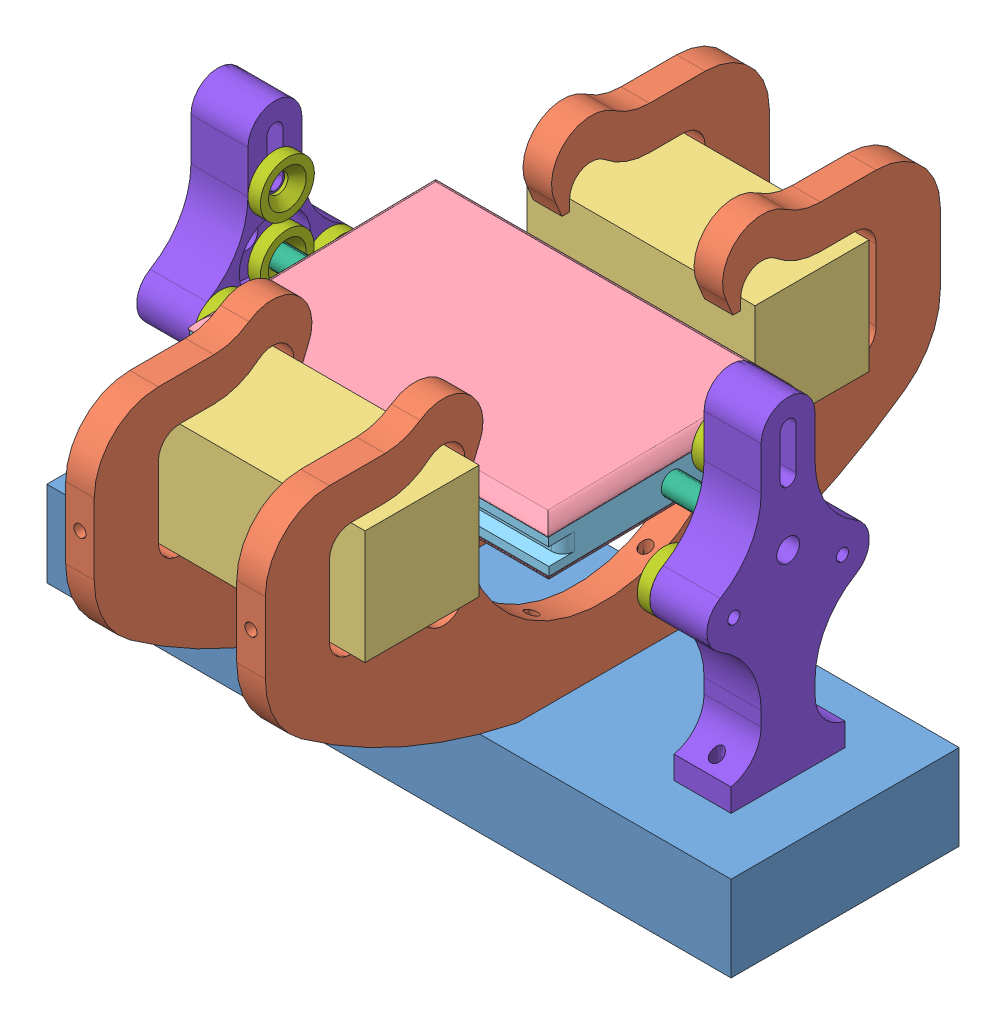
SolidWorks assembly solar motor, configuration Default. Lengths in mm.
Overall size (152.4 93 150.35).
19 component instances, 8 part files, 42 mates.
Components (placement in the parent):
- base-1: base [Default] at origin size (152.4 19.05 50.8)
- Magnet Support Arm-1: Magnet Support Arm [Default] at (53.975 63.5 25.4) x (0 0 -1) z (1 0 0) size (150.35 70.8 6.35)
- Magnet Support Arm-2: Magnet Support Arm [Default] at (92.075 63.5 25.4) x (0 0 -1) z (1 0 0) size (150.35 70.8 6.35)
- 1X1X2 c8 magnet-1: 1X1X2 c8 magnet [Default] at (101.6 50.8 -5.325) x (0 1 0) z (0 0 1) size (25.4 50.8 25.4)
- 1X1X2 c8 magnet-2: 1X1X2 c8 magnet [Default] at (50.8 50.8 81.525) x (0 0 -1) z (0 -1 0) size (25.4 50.8 25.4)
- 55X80 solar panel-1: 55X80 solar panel [Default] at (33.7861 66.8543 53.0591) x (1 0 0) z (0 0.999864 0.016493) size (80.15 55.15 2.73)
- Rotor Frame-1: Rotor Frame [Default] at (33.8861 59.237 52.8334) x (1 0 0) z (0 -0.016493 0.999864) size (80 7.62 55)
- 55X80 solar panel-2: 55X80 solar panel [Default] at (113.8861 59.2353 52.9334) x (-1 0 0) z (0 -0.999864 -0.016493) size (80.15 55.15 2.73)
- center rod-1: center rod [Default] at (26.3931 63.5 25.4) x (0 -0.960455 0.278435) z (0 0.278435 0.960455) size (4.9 99.57 4.9)
- magnet-1: magnet [Default] at (127 63.5 25.4) x (0 0.978601 0.205765) z (0 -0.205765 0.978601) size (12.01 2.78 12.01)
- magnet-2: magnet [Default] at (25.3543 63.5 25.4) x (0 -0.673541 -0.73915) z (0 -0.73915 0.673541) size (12.01 2.78 12.01)
- Rotor Suport-1: Rotor Suport [Default] at (12.7 63.5 25.4) x (0 0 -1) z (1 0 0) size (36.21 73.95 12.7)
- Rotor Suport-2: Rotor Suport [Default] at (139.7 63.5 25.4) x (0 0 1) z (-1 0 0) size (36.21 73.95 12.7)
- magnet-3: magnet [Default] at (25.4 77.47 25.4) x (0 -0.586567 -0.8099) z (0 -0.8099 0.586567) size (12.01 2.78 12.01)
- magnet-4: magnet [Default] at (25.4 56.515 37.4984) x (0 0.573393 -0.819281) z (0 -0.819281 -0.573393) size (12.01 2.78 12.01)
- magnet-5: magnet [Default] at (25.4 56.515 13.3016) x (0 0.225875 -0.974156) z (0 -0.974156 -0.225875) size (12.01 2.78 12.01)
- magnet-6: magnet [Default] at (127 77.47 25.4) x (0 0.532218 0.846608) z (0 -0.846608 0.532218) size (12.01 2.78 12.01)
- magnet-7: magnet [Default] at (127 56.515 37.4984) x (0 0.365722 0.930724) z (0 -0.930724 0.365722) size (12.01 2.78 12.01)
- magnet-8: magnet [Default] at (127 56.515 13.3016) x (0 0.869069 0.494691) z (0 -0.494691 0.869069) size (12.01 2.78 12.01)
Mates (geometry in assembly coordinates):
- Coincident1: coincident anti-aligned: plane of base-1 through (0 19.05 0) normal (0 1 0); plane of Magnet Support Arm-1 through (60.325 19.05 44.45) normal (0 -1 0)
- Coincident2: coincident anti-aligned: plane of base-1 through (0 19.05 0) normal (0 1 0); plane of Magnet Support Arm-2 through (98.425 19.05 44.45) normal (0 -1 0)
- Concentric1: concentric aligned: cylinder of base-1 through (95.25 19.05 12.7) axis (0 -1 0) radius 1.5875; cylinder of Magnet Support Arm-2 through (95.25 19.05 12.7) axis (0 -1 0) radius 1.3526
- Concentric2: concentric aligned: cylinder of base-1 through (95.25 19.05 38.1) axis (0 -1 0) radius 1.5875; cylinder of Magnet Support Arm-2 through (95.25 19.05 38.1) axis (0 -1 0) radius 1.3526
- Concentric3: concentric aligned: cylinder of base-1 through (57.15 19.05 38.1) axis (0 -1 0) radius 1.5875; cylinder of Magnet Support Arm-1 through (57.15 19.05 38.1) axis (0 -1 0) radius 1.3526
- Concentric4: concentric aligned: cylinder of base-1 through (57.15 19.05 12.7) axis (0 -1 0) radius 1.5875; cylinder of Magnet Support Arm-1 through (57.15 19.05 12.7) axis (0 -1 0) radius 1.3526
- Coincident3: coincident anti-aligned: plane of Magnet Support Arm-2 through (98.425 50.8 -30.725) normal (0 1 0); plane of 1X1X2 c8 magnet-1 through (50.8 50.8 -5.325) normal (0 -1 0)
- Coincident4: coincident anti-aligned: plane of Magnet Support Arm-2 through (98.425 50.8 -5.325) normal (0 0 -1); plane of 1X1X2 c8 magnet-1 through (50.8 50.8 -5.325) normal (0 0 1)
- Coincident5: coincident anti-aligned: plane of Magnet Support Arm-2 through (98.425 50.8 81.525) normal (0 1 0); plane of 1X1X2 c8 magnet-2 through (101.6 50.8 81.525) normal (0 -1 0)
- Coincident6: coincident anti-aligned: plane of Magnet Support Arm-1 through (60.325 50.8 56.125) normal (0 0 1); plane of 1X1X2 c8 magnet-2 through (101.6 50.8 56.125) normal (0 0 -1)
- Coincident7: coincident aligned: plane of 1X1X2 c8 magnet-1 through (101.6 50.8 -5.325) normal (1 0 0); plane of 1X1X2 c8 magnet-2 through (101.6 50.8 81.525) normal (1 0 0)
- Distance1: distance = 3.175 mm aligned: plane of Magnet Support Arm-2 through (98.425 71.4375 81.525) normal (1 0 0); plane of 1X1X2 c8 magnet-2 through (101.6 50.8 81.525) normal (1 0 0)
- Coincident9: coincident anti-aligned: plane of 55X80 solar panel-1 through (33.7861 66.8543 53.0591) normal (0 -0.999864 -0.016493); plane of Rotor Frame-1 through (33.8861 66.8559 52.9591) normal (0 0.999864 0.016493)
- Coincident10: coincident anti-aligned: plane of Rotor Frame-1 through (33.8861 59.237 52.8334) normal (0 -0.999864 -0.016493); plane of 55X80 solar panel-2 through (113.8861 59.2353 52.9334) normal (0 0.999864 0.016493)
- Coincident11: coincident aligned: plane of 55X80 solar panel-1 through (113.8861 69.5539 53.1036) normal (1 0 0); plane of 55X80 solar panel-2 through (113.8861 56.5357 52.8889) normal (1 0 0)
- Coincident12: coincident aligned: plane of 55X80 solar panel-1 through (33.7861 70.4627 -1.9889) normal (0 0.016493 -0.999864); plane of 55X80 solar panel-2 through (113.8861 57.4444 -2.2036) normal (0 0.016493 -0.999864)
- Coincident13: coincident aligned: plane of Rotor Frame-1 through (113.8861 66.8559 52.9591) normal (1 0 0); plane of 55X80 solar panel-2 through (113.8861 56.5357 52.8889) normal (1 0 0)
- Coincident14: coincident aligned: plane of 55X80 solar panel-1 through (33.7861 70.4627 -1.9889) normal (0 0.016493 -0.999864); plane of Rotor Frame-1 through (33.8861 67.763 -2.0334) normal (0 0.016493 -0.999864)
- Concentric5: concentric anti-aligned: cylinder of Magnet Support Arm-2 through (98.425 63.5 25.4) axis (-1 0 0) radius 30.725; cylinder of Rotor Frame-1 through (33.8861 63.5 25.4) axis (1 0 0) radius 2.4511
- Concentric6: concentric anti-aligned: cylinder of Rotor Frame-1 through (33.8861 63.5 25.4) axis (1 0 0) radius 2.4511; cylinder of center rod-1 through (125.9611 63.5 25.4) axis (-1 0 0) radius 2.4511
- Distance3: distance = 7.493 mm aligned: plane of center rod-1 through (26.3931 63.5 25.4) normal (-1 0 0); plane of Rotor Frame-1 through (33.8861 66.8559 52.9591) normal (-1 0 0)
- Coincident19: coincident anti-aligned: plane of base-1 through (0 19.05 0) normal (0 1 0); plane of Rotor Suport-2 through (127 19.05 25.4) normal (0 -1 0)
- Coincident20: coincident aligned: plane of Rotor Suport-1 through (25.4 19.05 25.4) normal (0 -1 0); plane of Rotor Suport-2 through (127 19.05 25.4) normal (0 -1 0)
- Coincident22: coincident aligned: plane of Rotor Suport-1 through (25.4 63.5 12.7) normal (0 0 -1); plane of Rotor Suport-2 through (127 63.5 12.7) normal (0 0 -1)
- Concentric9: concentric aligned: cylinder of base-1 through (133.35 19.05 15.875) axis (0 -1 0) radius 1.5875; cylinder of Rotor Suport-2 through (133.35 19.05 15.875) axis (0 -1 0) radius 1.3526
- Concentric10: concentric aligned: cylinder of base-1 through (19.05 19.05 34.925) axis (0 -1 0) radius 1.5875; cylinder of Rotor Suport-1 through (19.05 19.05 34.925) axis (0 -1 0) radius 1.3526
- Coincident31: coincident: circle of center rod-1; cone of magnet-2 through (26.101 63.5 25.4) axis (-1 0 0)
- Coincident32: coincident: circle of center rod-1; cone of magnet-1 through (126.2532 63.5 25.4) axis (1 0 0)
- Coincident33: coincident anti-aligned: plane of Rotor Suport-1 through (25.4 63.5 25.4) normal (1 0 0); plane of magnet-4 through (25.4 56.515 37.4984) normal (-1 0 0)
- Concentric11: concentric aligned: cylinder of Rotor Suport-1 through (12.7 56.515 37.4984) axis (-1 0 0) radius 1.3526; cylinder of magnet-4 through (28.1788 56.515 37.4984) axis (-1 0 0) radius 2.159
- Concentric12: concentric aligned: cylinder of Rotor Suport-1 through (25.4 77.47 25.4) axis (-1 0 0) radius 1.778; cylinder of magnet-3 through (28.1788 77.47 25.4) axis (-1 0 0) radius 2.159
- Coincident34: coincident anti-aligned: plane of Rotor Suport-1 through (25.4 63.5 25.4) normal (1 0 0); plane of magnet-3 through (25.4 77.47 25.4) normal (-1 0 0)
- Concentric13: concentric aligned: cylinder of Rotor Suport-1 through (12.7 56.515 13.3016) axis (-1 0 0) radius 1.3526; cylinder of magnet-5 through (28.1788 56.515 13.3016) axis (-1 0 0) radius 2.159
- Coincident35: coincident anti-aligned: plane of Rotor Suport-1 through (25.4 63.5 25.4) normal (1 0 0); plane of magnet-5 through (25.4 56.515 13.3016) normal (-1 0 0)
- Coincident36: coincident aligned: plane of magnet-6 through (127 77.47 25.4) normal (1 0 0); plane of magnet-7 through (127 56.515 37.4984) normal (1 0 0)
- Coincident37: coincident anti-aligned: plane of Rotor Suport-2 through (127 63.5 25.4) normal (-1 0 0); plane of magnet-6 through (127 77.47 25.4) normal (1 0 0)
- Coincident38: coincident anti-aligned: plane of Rotor Suport-2 through (127 63.5 25.4) normal (-1 0 0); plane of magnet-8 through (127 56.515 13.3016) normal (1 0 0)
- Coincident39: coincident anti-aligned: plane of Rotor Suport-2 through (127 63.5 25.4) normal (-1 0 0); plane of magnet-8 through (127 56.515 13.3016) normal (1 0 0)
- Concentric14: concentric aligned: cylinder of Rotor Suport-2 through (139.7 56.515 13.3016) axis (1 0 0) radius 1.3526; cylinder of magnet-8 through (124.2212 56.515 13.3016) axis (1 0 0) radius 2.159
- Concentric15: concentric aligned: cylinder of Rotor Suport-2 through (127 77.47 25.4) axis (1 0 0) radius 1.778; cylinder of magnet-6 through (124.2212 77.47 25.4) axis (1 0 0) radius 2.159
- Concentric16: concentric aligned: cylinder of Rotor Suport-2 through (139.7 56.515 37.4984) axis (1 0 0) radius 1.3526; cylinder of magnet-7 through (124.2212 56.515 37.4984) axis (1 0 0) radius 2.159
- Coincident40: coincident anti-aligned: plane of magnet-1 through (127 63.5 25.4) normal (1 0 0); plane of Rotor Suport-2 through (127 63.5 25.4) normal (-1 0 0)
